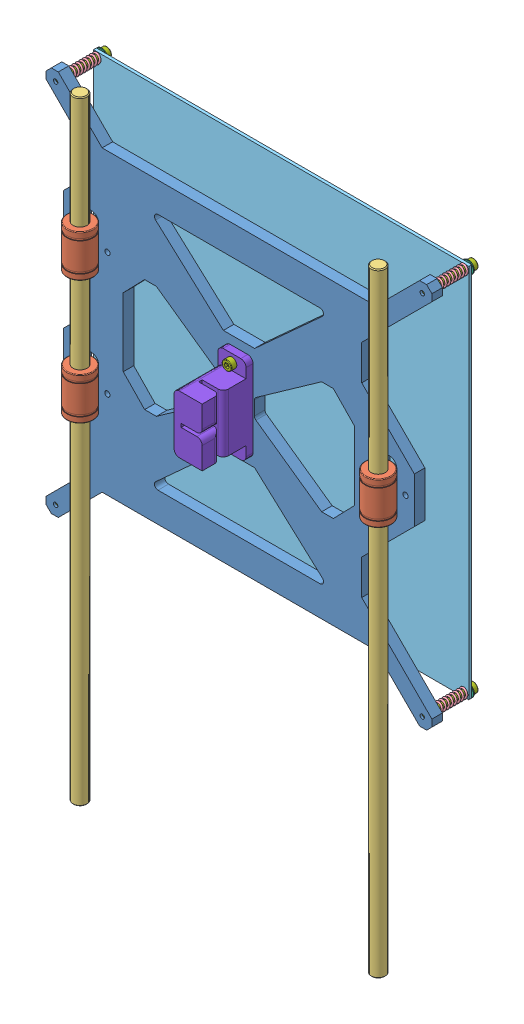
SolidWorks assembly Heated bed, configuration Default. Lengths in mm.
Overall size (220 350 58.21).
22 component instances, 8 part files, 37 mates.
Components (placement in the parent):
- bed-frame-1: bed-frame [Default] at (0.04 55.9824 0.0355) size (220 220 6)
- LMU8-1: LMU8 [Default] at (85.04 318.9895 11.6257) x (0 -1 0) z (-0.000862 0 1) size (24 15 15)
- LMU8-2: LMU8 [Default] at (255.04 257.9489 11.6257) x (0 1 0) z (0 0 1) size (24 15 15)
- LMU8-3: LMU8 [Default] at (85.04 224.4824 11.6257) x (0 1 0) z (-0.92596 0 0.377622) size (24 15 15)
- 8x350-Sm_Rod-1: 8x350-Sm_Rod [Default] at (85.04 382.9039 11.6257) x (0.720427 0 -0.693531) z (0 1 0) size (8 8 350)
- 8x350-Sm_Rod-2: 8x350-Sm_Rod [Default] at (255.04 32.9039 11.6257) x (0.743236 0 -0.669029) z (0 -1 0) size (8 8 350)
- spring-1: spring [Default] at (274.54 375.4824 -17.9745) x (0.611768 -0.791037 0) z (-0.791037 -0.611768 0) size (5.71 21.23 5.77)
- spring-3: spring [Default] at (274.54 166.4824 -17.9745) x (1 0 0) z (0 -1 0) size (5.71 21.23 5.77)
- spring-5: spring [Default] at (65.54 166.4824 -17.9745) x (-0.878714 -0.477349 0) z (-0.477349 0.878714 0) size (5.71 21.23 5.77)
- spring-7: spring [Default] at (65.54 375.4824 -17.9745) x (0.923817 0.382834 0) z (0.382834 -0.923817 0) size (5.71 21.23 5.77)
- HEATBED MK2 200x200-1: HEATBED MK2 200x200 [Default] at (277.04 163.9824 -19.6745) x (-1 0 0) z (0 0 -1) size (214 214 1.7)
- Plain washer-1: Plain washer [M3 plain washer] at (65.54 375.4824 -20.1745) x (0 0 -1) z (0.999794 -0.020314 0) size (0.5 7 7)
- Socket head cap screw-1: Socket head cap screw [M3x25] at (65.54 375.4824 -23.1745) x (0 0 1) z (0.313828 -0.94948 0) size (28 5.5 5.5)
- Socket head cap screw-2: Socket head cap screw [M3x25] at (65.54 166.4824 -23.1745) x (0 0 1) z (0.313828 -0.94948 0) size (28 5.5 5.5)
- Plain washer-2: Plain washer [M3 plain washer] at (65.54 166.4824 -20.1745) x (0 0 -1) z (0.999794 -0.020314 0) size (0.5 7 7)
- Plain washer-3: Plain washer [M3 plain washer] at (274.54 375.4824 -20.1745) x (0 0 -1) z (0.999794 -0.020314 0) size (0.5 7 7)
- Plain washer-4: Plain washer [M3 plain washer] at (274.54 166.4824 -20.1745) x (0 0 -1) z (0.999794 -0.020314 0) size (0.5 7 7)
- Socket head cap screw-3: Socket head cap screw [M3x25] at (274.54 375.4824 -23.1745) x (0 0 1) z (0.313828 -0.94948 0) size (28 5.5 5.5)
- Socket head cap screw-4: Socket head cap screw [M3x25] at (274.54 166.4824 -23.1745) x (0 0 1) z (0.313828 -0.94948 0) size (28 5.5 5.5)
- Y Belt Holder-1: Y Belt Holder [Default] at (178.0647 270.4824 20.5355) x (0 1 0) z (1 0 0) size (50 29 16)
- Socket head cap screw-5: Socket head cap screw [M3x12] at (170.0647 290.9824 13.0355) x (0 0 -1) z (0.865356 -0.501158 0) size (15 5.5 5.5)
- Socket head cap screw-9: Socket head cap screw [M3x12] at (170.0647 249.9824 13.0355) x (0 0 -1) z (0.844505 -0.535547 0) size (15 5.5 5.5)
Mates (geometry in assembly coordinates):
- Coincident3: coincident: line of bed-frame-1 through (260.04 258.8453 6.0355) axis (0 1 0); cylinder of LMU8-2 through (255.04 257.9477 11.6257) axis (0 1 0) radius 7.5
- Coincident7: coincident: line of bed-frame-1 through (90.04 224.9824 6.0355) axis (0 1 0); cylinder of LMU8-3 through (85.04 224.4812 11.6257) axis (0 1 0) radius 7.5
- Coincident8: coincident anti-aligned: axis of LMU8-1 through (85.04 299.6329 11.6257) axis (0 -1 0); axis of LMU8-3 through (85.04 220.639 11.6257) axis (0 1 0)
- Concentric2: concentric anti-aligned: cylinder of LMU8-1 through (85.04 318.9907 11.6257) axis (0 -1 0) radius 4; cylinder of 8x350-Sm_Rod-1 through (85.04 32.9039 11.6257) axis (0 1 0) radius 4
- Concentric7: concentric anti-aligned: cylinder of LMU8-2 through (255.04 257.9477 11.6257) axis (0 1 0) radius 4; cylinder of 8x350-Sm_Rod-2 through (255.04 382.9039 11.6257) axis (0 -1 0) radius 4
- Coincident10: coincident aligned: plane of 8x350-Sm_Rod-1 through (85.04 32.9039 11.6257) normal (0 -1 0); plane of 8x350-Sm_Rod-2 through (255.04 32.9039 11.6257) normal (0 -1 0)
- Coincident11: coincident: line of bed-frame-1 through (80.04 247.9824 6.0355) axis (0 -1 0); cylinder of LMU8-3 through (85.04 224.4812 11.6257) axis (0 1 0) radius 7.5
- Coincident12: coincident: line of bed-frame-1 through (80.04 317.9895 6.0355) axis (0 -1 0); cylinder of LMU8-1 through (85.04 318.9907 11.6257) axis (0 -1 0) radius 7.5
- Coincident14: coincident: line of bed-frame-1 through (250.04 281.8453 6.0355) axis (0 -1 0); cylinder of LMU8-2 through (255.04 257.9477 11.6257) axis (0 1 0) radius 7.5
- Parallel4: parallel anti-aligned: plane of bed-frame-1 through (0.04 55.9824 0.0355) normal (0 0 -1); plane of assembly through (0 0 0) normal (0 0 1)
- Distance1: distance = 3 mm anti-aligned: plane of bed-frame-1 through (84.04 321.9895 6.0355) normal (0 -1 0); plane of LMU8-1 through (92.14 318.9895 11.6318) normal (0 1 0)
- Distance2: distance = 3.5 mm anti-aligned: plane of LMU8-3 through (83.5295 248.4824 7.9219) normal (0 1 0); plane of bed-frame-1 through (84.04 251.9824 6.0355) normal (0 -1 0)
- Distance3: distance = 3.8964 mm anti-aligned: plane of LMU8-2 through (251.04 281.9489 11.6257) normal (0 1 0); plane of bed-frame-1 through (254.04 285.8453 6.0355) normal (0 -1 0)
- Concentric8: concentric aligned: circle of bed-frame-1; circle of spring-5
- Concentric9: concentric aligned: circle of bed-frame-1; circle of spring-7
- Concentric10: concentric aligned: circle of bed-frame-1; circle of spring-1
- Concentric11: concentric aligned: circle of bed-frame-1; circle of spring-3
- Coincident15: coincident anti-aligned: plane of bed-frame-1 through (0.04 55.9824 0.0355) normal (0 0 -1); plane of spring-3 through (274.54 166.4824 0.0355) normal (0 0 1)
- Coincident16: coincident anti-aligned: plane of bed-frame-1 through (0.04 55.9824 0.0355) normal (0 0 -1); circle of spring-1
- Coincident17: coincident anti-aligned: plane of bed-frame-1 through (0.04 55.9824 0.0355) normal (0 0 -1); plane of spring-7 through (65.54 375.4824 0.0355) normal (0 0 1)
- Coincident18: coincident anti-aligned: plane of bed-frame-1 through (0.04 55.9824 0.0355) normal (0 0 -1); plane of spring-5 through (65.54 166.4824 0.0355) normal (0 0 1)
- Concentric12: concentric aligned: cylinder of bed-frame-1 through (274.54 375.4824 6.0355) axis (0 0 -1) radius 1.25; cylinder of Socket head cap screw-3 through (274.54 375.4824 -54.9245) axis (0 0 -1) radius 1.5
- Concentric13: concentric aligned: cylinder of bed-frame-1 through (274.54 167.985 17.2159) axis (0 0 -1) radius 1.5; cylinder of ? through (274.54 167.985 2.2837) axis (0 0 -1) radius 1.5
- Concentric15: concentric aligned: cylinder of bed-frame-1 through (65.54 375.4824 6.0355) axis (0 0 -1) radius 1.25; cylinder of Socket head cap screw-1 through (65.54 375.4824 -54.9245) axis (0 0 -1) radius 1.5
- Concentric19: concentric anti-aligned: cylinder of Plain washer-1 through (65.54 375.4824 14.7505) axis (0 0 1) radius 1.6; cylinder of Socket head cap screw-1 through (65.54 375.4824 -54.9245) axis (0 0 -1) radius 1.5
- Coincident22: coincident anti-aligned: plane of Plain washer-1 through (65.5725 377.0821 -20.1745) normal (0 0 -1); plane of Socket head cap screw-1 through (62.9289 374.6194 -20.1745) normal (0 0 1)
- Coincident23: coincident anti-aligned: plane of HEATBED MK2 200x200-1 through (277.04 163.9824 -19.6745) normal (0 0 -1); plane of Plain washer-1 through (65.6111 378.9817 -19.6745) normal (0 0 1)
- Concentric20: concentric anti-aligned: circle of bed-frame-1; circle of HEATBED MK2 200x200-1
- Concentric21: concentric anti-aligned: circle of bed-frame-1; circle of HEATBED MK2 200x200-1
- Coincident27: coincident anti-aligned: plane of spring-5 through (62.5233 161.5611 -17.9745) normal (0 0 -1); plane of HEATBED MK2 200x200-1 through (277.04 163.9824 -17.9745) normal (0 0 1)
- Concentric22: concentric anti-aligned: cylinder of Socket head cap screw-2 through (65.54 166.4824 -54.9245) axis (0 0 -1) radius 1.5; cylinder of ? through (65.54 166.4824 7.4255) axis (0 0 1) radius 1.25
- Distance4: coincident aligned: plane of Socket head cap screw-2 through (64.3821 166.0997 9.8255) normal (0 0 1); plane of ? through (65.54 169.6579 9.8255) normal (0 0 1)
- Coincident28: coincident anti-aligned: plane of bed-frame-1 through (0.04 55.9824 6.0355) normal (0 0 1); plane of Y Belt Holder-1 through (162.0647 270.4824 6.0355) normal (0 0 -1)
- Concentric26: concentric anti-aligned: cylinder of Y Belt Holder-1 through (170.0647 290.9824 14.2782) axis (0 0 -1) radius 1.5; cylinder of Socket head cap screw-5 through (170.0647 290.9824 44.7855) axis (0 0 1) radius 1.5
- Concentric29: concentric anti-aligned: cylinder of Y Belt Holder-1 through (170.0647 249.9824 14.2782) axis (0 0 -1) radius 1.5; cylinder of Socket head cap screw-9 through (170.0647 249.9824 44.7855) axis (0 0 1) radius 1.5
- Coincident32: coincident anti-aligned: plane of Y Belt Holder-1 through (162.0647 270.4824 10.0355) normal (0 0 1); plane of Socket head cap screw-9 through (171.5374 252.3048 10.0355) normal (0 0 -1)
- Coincident33: coincident anti-aligned: plane of Y Belt Holder-1 through (162.0647 270.4824 10.0355) normal (0 0 1); plane of Socket head cap screw-5 through (171.4429 293.3622 10.0355) normal (0 0 -1)
